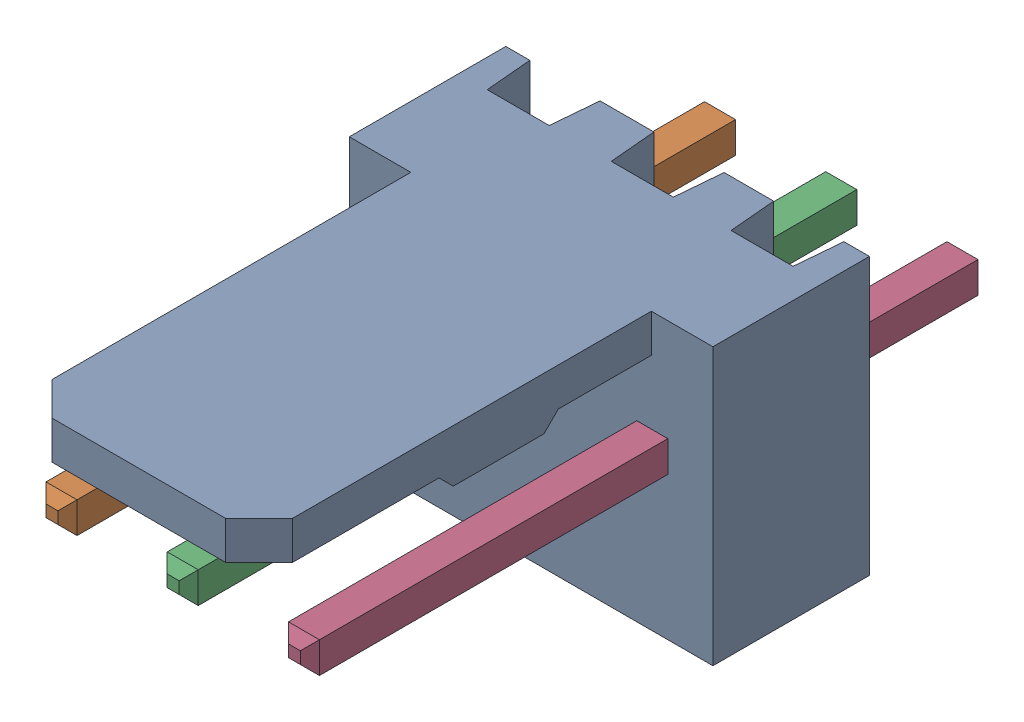
SolidWorks assembly Molex PCB 3 pin v2 v6_1, configuration Default. Lengths in mm.
Overall size (7.62 5.79 14.92).
4 component instances, 2 part files, 0 mates.
Components (placement in the parent):
- BASE9710016_2-1: BASE9710016_2 [Default] at (2.54 2.895 -8.22) size (7.62 5.79 11.5)
- PINO9710016_2-1: PINO9710016_2 [Default] at (1.27 3.325 -0.72) size (0.65 0.65 14.2)
- PINO9710016_2-2: PINO9710016_2 [Default] at (3.81 3.325 -0.72) size (0.65 0.65 14.2)
- PINO9710016_2-3: PINO9710016_2 [Default] at (6.35 3.325 -0.72) size (0.65 0.65 14.2)
